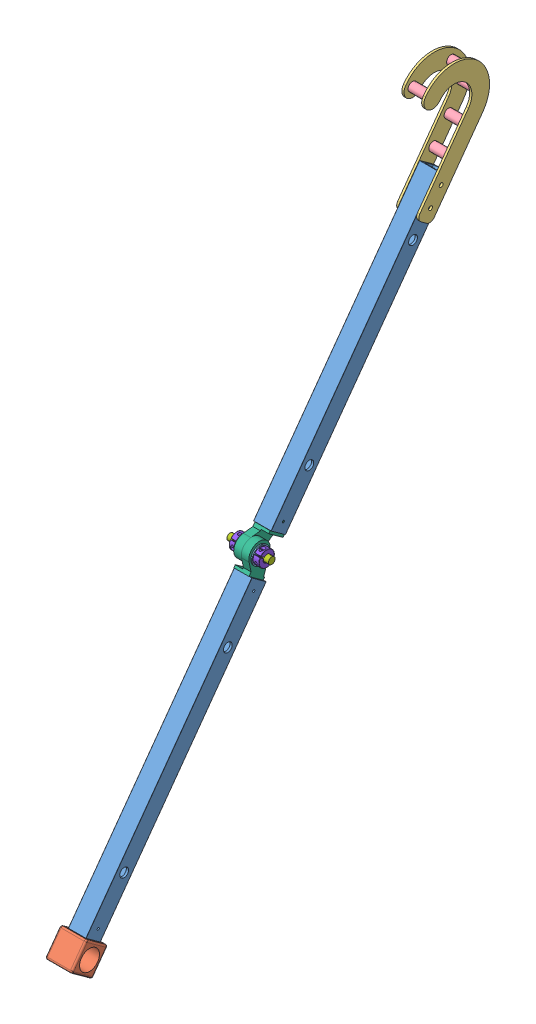
SolidWorks assembly new endcaps other side of climber, configuration Default. Lengths in mm.
Overall size (59.8 894.39 626.35).
19 component instances, 9 part files, 33 mates.
Components (placement in the parent):
- chasis box for climber prototype-1: chasis box for climber prototype [Default] at (1583.147 1030.9002 1775.5006) size (711.2 101.6 711.2) (hidden)
- 1x1x20 box extrusion for climber-1: 1x1x20 box extrusion for climber [Default] at (1887.947 1461.6614 1740.3441) x (1 0 0) z (0 -0.809944 0.586507) size (25.4 25.4 406.4)
- 1x1x20 box extrusion for climber-2: 1x1x20 box extrusion for climber [Default] at (1885.272 1832.7584 1471.6205) x (1 0 0) z (0 -0.809944 0.586507) size (25.4 25.4 406.4)
- End Bearing Holder-2: End Bearing Holder [Default] at (1900.012 1149.8627 1981.024) x (0 -0.586507 -0.809944) z (-1 0 0) size (38.1 50.8 38.1)
- Candy cane claw-3: Candy cane claw [Default] at (1910.672 1798.5654 1518.3043) x (0 -0.586507 -0.809944) z (1 0 0) size (101.6 177.8 3.17)
- Candy cane claw-4: Candy cane claw [Default] at (1882.097 1798.5654 1518.3043) x (0 -0.586507 -0.809944) z (1 0 0) size (101.6 177.8 3.17)
- 1in Spacers-1: 1in Spacers [Default] at (1910.672 1944.5724 1502.1897) x (-1 0 0) z (0 -0.269928 0.96288) size (25.4 12.7 12.7)
- 1in Spacers-2: 1in Spacers [Default] at (1885.272 1855.4215 1472.3876) x (1 0 0) z (0 0.99299 -0.118201) size (25.4 12.7 12.7)
- 1in Spacers-3: 1in Spacers [Default] at (1885.272 1885.4627 1450.4191) x (1 0 0) z (0 0.99299 -0.118201) size (25.4 12.7 12.7)
- 1in Spacers-4: 1in Spacers [Default] at (1885.272 1920.3809 1433.5576) x (1 0 0) z (0 0.99299 -0.118201) size (25.4 12.7 12.7)
- 1in Spacers-5: 1in Spacers [Default] at (1885.272 1950.2788 1446.7848) x (1 0 0) z (0 0.99299 -0.118201) size (25.4 12.7 12.7)
- AA Climb Insert v2-1: AA Climb Insert v2 [Default] at (1892.8409 1446.2027 1684.5075) x (0 -0.586507 -0.809944) z (0 -0.809944 0.586507) size (40.77 59.8 124.78)
  - Ball Bearing-1: Ball Bearing [Default] at (-81.0287 -2.4491 -5.6602) x (1 0 0) z (0 1 0) size (25.4 25.4 10.32)
  - Climber Insert 1-1: Climber Insert 1 [Default] at (-79.4412 -4.6438 -68.0482) size (40.77 21.73 77.76)
  - Ball Bearing-2: Ball Bearing [Default] at (-81.0287 15.3865 -4.7702) x (1 0 0) z (0 -1 0) size (25.4 25.4 10.32)
  - Climber Insert 1-2: Climber Insert 1 [Default] at (-79.4412 17.5812 56.7279) x (1 0 0) z (0 0 -1) size (40.77 21.73 77.76)
  - Rotary Shaft-1: Rotary Shaft [Default] at (-81.0287 -2.4491 -5.6602) x (1 0 0) z (0 -1 0) size (9.53 9.53 59.8)
  - Clamping Two-Piece Shaft Collar-1: Clamping Two-Piece Shaft Collar [Default] at (-81.0287 -10.5629 -5.6602) x (1 0 0) z (0 -1 0) size (22.18 22.23 9.54)
  - Clamping Two-Piece Shaft Collar-2: Clamping Two-Piece Shaft Collar [Default] at (-81.0287 23.5002 -4.7702) x (1 0 0) z (0 1 0) size (22.18 22.23 9.54)
Mates (geometry in assembly coordinates):
- Concentric15: concentric aligned: cylinder of Bracket for climber prototype-6 through (1914.9212 1625.177 2102.2707) axis (-0.999875 -0.007701 -0.013823) radius 2.667; cylinder of Candy cane claw-2 through (1890.2863 1624.9873 2101.9302) axis (-0.999875 -0.007701 -0.013823) radius 2.794
- Coincident16: coincident anti-aligned: plane of Bracket for climber prototype-6 through (1886.9489 1640.7303 2104.8766) normal (0.999875 0.007701 0.013823); plane of Candy cane claw-2 through (1885.7727 1632.8052 2194.3729) normal (-0.999875 -0.007701 -0.013823)
- Coincident42: coincident aligned: line of chasis box for climber prototype-1 through (1913.347 1132.5002 1978.7006) axis (-1 0 0); line of 1x1x20 box extrusion for climber-1 through (1913.093 1132.5002 1978.7006) axis (-1 0 0)
- Coincident43: coincident aligned: plane of chasis box for climber prototype-1 through (1913.347 1132.5002 1978.7006) normal (1 0 0); plane of 1x1x20 box extrusion for climber-1 through (1913.347 1147.2485 1999.0675) normal (1 0 0)
- Coincident52: coincident anti-aligned: plane of half in hex bearing for clibmer-2 through (1948.0967 1646.3247 2062.7265) normal (0 0.873592 -0.486659); plane of 1x1x20 box extrusion for climber-2 through (1927.571 1492.6353 1757.0397) normal (0 -0.550312 0.834959)
- Tangent7: tangent anti-aligned: plane of 1x1x20 box extrusion for climber-1 through (1888.201 1147.5401 1999.1692) normal (0 0.592122 0.805848); cylinder of left Torsion Spring-1 through (1906.997 1485.0314 1713.7041) axis (0 -0.760895 0.648876) radius 1.7145
- Distance9: distance = 6.35 mm: plane of 1x1x20 box extrusion for climber-1 through (1913.347 1147.3897 1998.9645) normal (1 0 0); cylinder of left Torsion Spring-1 through (1906.997 1485.0314 1713.7041) axis (0 -0.760895 0.648876) radius 1.7145
- Tangent12: tangent anti-aligned: plane of ? through (1888.201 1147.5401 1999.1692) normal (0 0.592122 0.805848); face of ?
- Coincident81: coincident anti-aligned: plane of 1x1x20 box extrusion for climber-1 through (1891.122 1144.6042 1995.4159) normal (1 0 0); plane of End Bearing Holder-2 through (1891.122 1144.7905 1995.673) normal (-1 0 0)
- Coincident82: coincident anti-aligned: plane of 1x1x20 box extrusion for climber-1 through (1892.7095 1134.3624 1981.2722) normal (0 0.586507 0.809944); plane of End Bearing Holder-2 through (1891.122 1134.3624 1981.2722) normal (0 -0.586507 -0.809944)
- Coincident83: coincident anti-aligned: plane of 1x1x20 box extrusion for climber-1 through (1888.201 1132.6492 1978.9064) normal (0 -0.809944 0.586507); plane of End Bearing Holder-2 through (1900.012 1139.5764 1988.4726) normal (0 0.809944 -0.586507)
- Coincident92: coincident anti-aligned: plane of 1x1x20 box extrusion for climber-2 through (1885.272 1536.4544 1686.4976) normal (-1 0 0); plane of Candy cane claw-4 through (1885.272 1953.6999 1447.1489) normal (1 0 0)
- Concentric40: concentric aligned: circle of 1x1x20 box extrusion for climber-2; cylinder of Candy cane claw-4 through (1885.272 1862.78 1465.8745) axis (-1 0 0) radius 2.794
- Parallel1: parallel aligned: plane of 1x1x20 box extrusion for climber-2 through (1885.526 1551.2027 1706.8645) normal (0 0.586507 0.809944); plane of Candy cane claw-4 through (1885.272 1842.1115 1496.5935) normal (0 0.586507 0.809944)
- Coincident94: coincident anti-aligned: plane of 1x1x20 box extrusion for climber-2 through (1910.672 1551.0537 1706.6587) normal (1 0 0); plane of Candy cane claw-3 through (1910.672 1953.6999 1447.1489) normal (-1 0 0)
- Concentric41: concentric anti-aligned: cylinder of 1x1x20 box extrusion for climber-2 through (1910.672 1862.78 1465.8745) axis (-1 0 0) radius 1.5875; circle of Candy cane claw-3
- Parallel2: parallel aligned: plane of 1x1x20 box extrusion for climber-2 through (1910.418 1536.3054 1686.2919) normal (0 -0.586507 -0.809944); plane of Candy cane claw-3 through (1913.847 1827.2142 1476.021) normal (0 -0.586507 -0.809944)
- Coincident96: coincident anti-aligned: plane of Candy cane claw-3 through (1910.672 1953.6999 1447.1489) normal (-1 0 0); plane of 1in Spacers-2 through (1910.672 1888.1298 1448.7025) normal (1 0 0)
- Coincident97: coincident anti-aligned: plane of Candy cane claw-3 through (1910.672 1953.6999 1447.1489) normal (-1 0 0); circle of 1in Spacers-3
- Coincident98: coincident anti-aligned: plane of Candy cane claw-4 through (1885.272 1953.6999 1447.1489) normal (1 0 0); plane of 1in Spacers-4 through (1885.272 1953.0892 1409.8724) normal (-1 0 0)
- Coincident99: coincident anti-aligned: plane of Candy cane claw-3 through (1910.672 1953.6999 1447.1489) normal (-1 0 0); plane of 1in Spacers-5 through (1910.672 1982.987 1423.0997) normal (1 0 0)
- Coincident100: coincident anti-aligned: plane of Candy cane claw-4 through (1885.272 1953.6999 1447.1489) normal (1 0 0); plane of 1in Spacers-1 through (1885.272 1977.2806 1478.5046) normal (-1 0 0)
- Lock1: lock: unknown of Candy cane claw-3; unknown of 1in Spacers-3
- Lock2: lock: unknown of Candy cane claw-3; unknown of 1in Spacers-4
- Lock3: lock: unknown of Candy cane claw-3; unknown of 1in Spacers-5
- Lock4: lock: unknown of Candy cane claw-3; unknown of 1in Spacers-1
- Lock5: lock: unknown of Candy cane claw-3; unknown of 1in Spacers-2
- Coincident101: coincident anti-aligned: plane of 1x1x20 box extrusion for climber-1 through (1892.7095 1134.3624 1981.2722) normal (0 0.586507 0.809944); plane of AA Climb Insert v2-1/Climber Insert 1-2 through (1910.172 1433.9606 1764.3232) normal (0 -0.586507 -0.809944)
- Coincident102: coincident anti-aligned: plane of 1x1x20 box extrusion for climber-1 through (1910.172 1135.2934 1982.558) normal (-1 0 0); plane of AA Climb Insert v2-1/Climber Insert 1-2 through (1910.172 1446.7025 1781.9192) normal (1 0 0)
- Coincident103: coincident anti-aligned: plane of 1x1x20 box extrusion for climber-1 through (1888.201 1461.8104 1740.5498) normal (0 0.809944 -0.586507); plane of AA Climb Insert v2-1/Climber Insert 1-2 through (1910.172 1462.4459 1741.4274) normal (0 -0.809944 0.586507)
- Coincident104: coincident anti-aligned: plane of 1x1x20 box extrusion for climber-2 through (1890.0345 1505.4593 1712.5486) normal (0 0.586507 0.809944); plane of AA Climb Insert v2-1/Climber Insert 1-1 through (1888.447 1535.0222 1691.1411) normal (0 -0.586507 -0.809944)
- Coincident105: coincident anti-aligned: plane of 1x1x20 box extrusion for climber-2 through (1888.447 1515.7012 1726.6923) normal (1 0 0); plane of AA Climb Insert v2-1/Climber Insert 1-1 through (1888.447 1547.7641 1708.7371) normal (-1 0 0)
- Coincident106: coincident anti-aligned: plane of 1x1x20 box extrusion for climber-2 through (1885.526 1503.7461 1710.1828) normal (0 -0.809944 0.586507); plane of AA Climb Insert v2-1/Climber Insert 1-1 through (1888.447 1504.3816 1711.0603) normal (0 0.809944 -0.586507)
